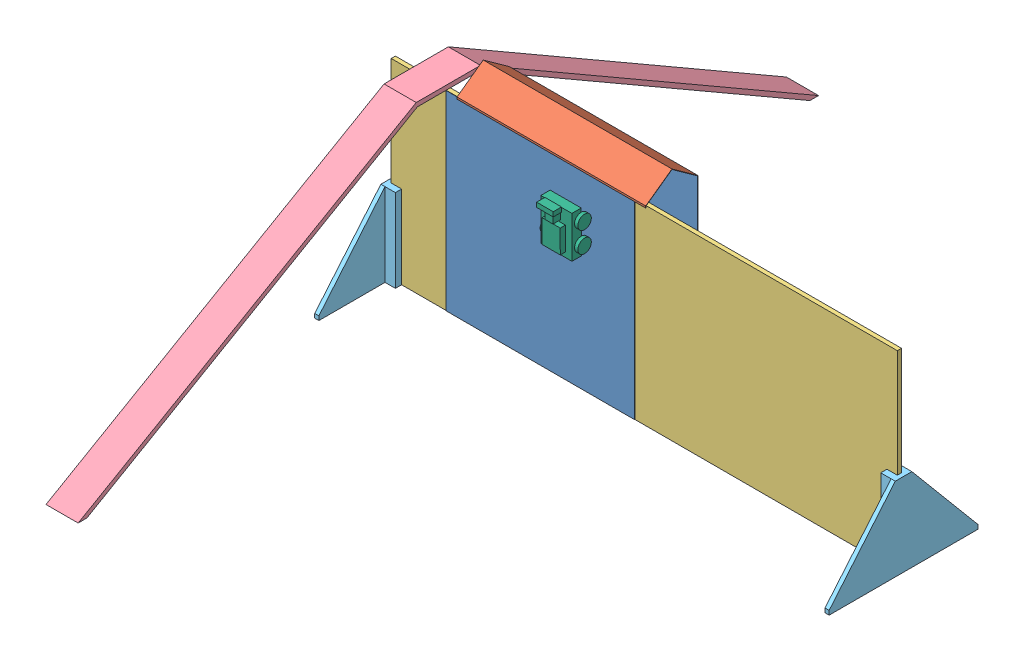
SolidWorks assembly Wall Assembly, configuration Default. Lengths in mm.
Overall size (2480 1011.85 3569.72).
8 component instances, 6 part files, 18 mates.
Components (placement in the parent):
- Metal Face-1: Metal Face [Default] at (533.6414 71.3319 -112.9215) x (1 0 0) z (0 -1 0) size (910 1.5 920)
- Metal Triangle-1: Metal Triangle [Default] at (133.6414 531.3319 -236.4215) size (910 100.15 253.1)
- Wall-1: Wall [Default] at (1033.6414 71.3319 -132.9215) x (1 0 0) z (0 -1 0) size (2440 20 920)
- Wooden Ramp-1: Wooden Ramp [Default] at (-76.3586 -388.6681 -123.2946) size (155 941 3569.72)
- Wooden Support-1: Wooden Support [Default] at (-206.3586 -388.6681 -122.9215) size (70 400 717.72)
- Wooden Support-2: Wooden Support [Default] at (2273.6414 -388.6681 -122.9215) x (-1 0 0) z (0 0 -1) size (70 400 717.72)
- Metal Face-2: Metal Face [Default] at (588.6414 71.3319 -361.4215) x (1 0 0) z (0 -1 0) size (910 1.5 920)
- Design 1-1: Design 1 [Default] at (688.6877 298.8253 -79.0056) x (0.001815 -0.999998 0) z (-0.999998 -0.001815 0) size (217 132.5 182)
Mates (geometry in assembly coordinates):
- Coincident4: coincident aligned: plane of Wall-1 through (-186.3586 -388.6681 -112.9215) normal (0 -1 0); plane of Wooden Support-1 through (-186.3586 -388.6681 235.9363) normal (0 -1 0)
- Coincident5: coincident anti-aligned: plane of Wall-1 through (-186.3586 -388.6681 -112.9215) normal (-1 0 0); plane of Wooden Support-1 through (-186.3586 -388.6681 -122.9215) normal (1 0 0)
- Coincident6: coincident aligned: plane of Wall-1 through (-186.3586 -388.6681 -112.9215) normal (0 -1 0); plane of Wooden Support-2 through (2253.6414 -388.6681 -481.7794) normal (0 -1 0)
- Coincident7: coincident anti-aligned: plane of Wall-1 through (2253.6414 -388.6681 -112.9215) normal (1 0 0); plane of Wooden Support-2 through (2253.6414 -388.6681 -122.9215) normal (-1 0 0)
- Coincident8: coincident anti-aligned: plane of Wall-1 through (1033.6414 71.3319 -112.9215) normal (0 0 1); plane of Wooden Support-2 through (2203.6414 11.3319 -112.9215) normal (0 0 -1)
- Coincident9: coincident anti-aligned: plane of Wall-1 through (1033.6414 71.3319 -112.9215) normal (0 0 1); plane of Wooden Support-1 through (-136.3586 11.3319 -112.9215) normal (0 0 -1)
- Coincident10: coincident aligned: plane of Metal Face-1 through (78.6414 -388.6681 -111.4215) normal (0 -1 0); plane of Wall-1 through (-186.3586 -388.6681 -112.9215) normal (0 -1 0)
- Coincident11: coincident anti-aligned: plane of Metal Face-1 through (533.6414 71.3319 -112.9215) normal (0 0 -1); plane of Wall-1 through (1033.6414 71.3319 -112.9215) normal (0 0 1)
- Coincident12: coincident anti-aligned: plane of Metal Face-1 through (533.6414 71.3319 -111.4215) normal (0 0 1); plane of Metal Triangle-1 through (1043.6414 531.3319 -111.4215) normal (0 0 -1)
- Distance1: distance = 265 mm aligned: plane of Wall-1 through (-186.3586 -388.6681 -112.9215) normal (-1 0 0); plane of Metal Face-1 through (78.6414 -388.6681 -111.4215) normal (-1 0 0)
- Distance2: distance = 55 mm aligned: plane of Metal Face-1 through (78.6414 -388.6681 -111.4215) normal (-1 0 0); plane of Metal Triangle-1 through (133.6414 531.3319 -236.4215) normal (-1 0 0)
- Coincident15: coincident aligned: line of Metal Face-1 through (988.6414 531.3319 -111.4215) axis (-1 0 0); line of Metal Triangle-1 through (1043.6414 531.3319 -111.4215) axis (-1 0 0)
- Coincident16: coincident aligned: plane of Metal Triangle-1 through (1043.6414 531.3319 -236.4215) normal (1 0 0); plane of Metal Face-2 through (1043.6414 -388.6681 -359.9215) normal (1 0 0)
- Coincident17: coincident aligned: line of Metal Triangle-1 through (1043.6414 531.3319 -361.4215) axis (-1 0 0); line of Metal Face-2 through (1043.6414 531.3319 -361.4215) axis (-1 0 0)
- Coincident18: coincident anti-aligned: plane of Wall-1 through (-186.3586 531.3319 -112.9215) normal (0 1 0); plane of Wooden Ramp-1 through (78.6414 531.3319 -123.2946) normal (0 -1 0)
- Distance3: distance = 110 mm aligned: plane of Wooden Ramp-1 through (-76.3586 -388.6681 -123.2946) normal (-1 0 0); plane of Wall-1 through (-186.3586 -388.6681 -112.9215) normal (-1 0 0)
- Distance5: distance = 139 mm: line of Wooden Ramp-1 through (78.6414 531.3319 26.0785) axis (-1 0 0); line of Wall-1 through (2253.6414 531.3319 -112.9215) axis (-1 0 0)
- Parallel1: parallel anti-aligned: plane of Metal Face-1 through (533.6414 71.3319 -111.4215) normal (0 0 1); plane of Design 1-1 through (688.6877 298.8253 -79.0056) normal (0 0 -1)
